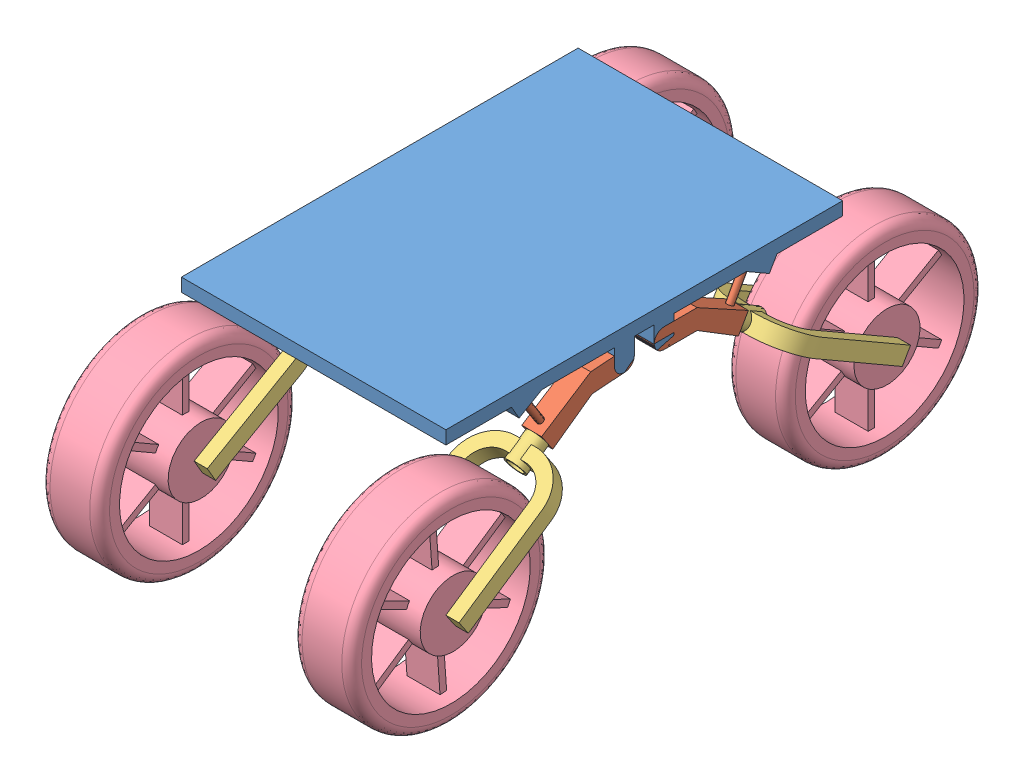
SolidWorks assembly Montagem, configuration Default. Lengths in mm.
Overall size (512.03 470.84 1081.65).
21 component instances, 4 part files, 4 mates.
Components (placement in the parent):
- Base_Boneco-1: Base_Boneco [Default] at (96.9313 339.3056 509.7897) size (400 60 600)
- Amortecimento&Motor-1: Amortecimento&Motor [Default] at (-88.0687 314.3056 479.7897) x (0 0 -1) z (1 0 0) size (523.5 434.65 142.03)
  - Suporte_Rodas-1: Suporte_Rodas [Default] at origin size (166.98 93.59 30)
  - Chave&Motor-1: Chave&Motor [Default] at (303.5974 -146.4145 0) x (0 0 1) z (-0.5 -0.866025 0) size (142.03 362 300)
    - Chave_Motor-1: Chave_Motor [Default] at origin size (142.03 220 30)
    - Motor_Roda-2: Motor_Roda [Default] x (0 0 -1) z (1 0 0) size (300 300 97)
- Amortecimento&Motor-2: Amortecimento&Motor [Default] at (281.9313 314.3056 479.7897) x (0 0 -1) z (1 0 0) size (523.5 434.65 142.03)
  - Suporte_Rodas-1: Suporte_Rodas [Default] at origin size (166.98 93.59 30)
  - Chave&Motor-1: Chave&Motor [Default] at (303.5974 -146.4145 0) x (0 0 1) z (-0.5 -0.866025 0) size (142.03 362 300)
    - Chave_Motor-1: Chave_Motor [Default] at origin size (142.03 220 30)
    - Motor_Roda-2: Motor_Roda [Default] x (0 0 -1) z (1 0 0) size (300 300 97)
- Amortecimento&Motor-3: Amortecimento&Motor [Default] at (-88.0687 314.3056 539.7897) x (0 0 1) z (-1 0 0) size (523.5 434.65 142.03)
  - Suporte_Rodas-1: Suporte_Rodas [Default] at origin size (166.98 93.59 30)
  - Chave&Motor-1: Chave&Motor [Default] at (303.5974 -146.4145 0) x (0 0 1) z (-0.5 -0.866025 0) size (142.03 362 300)
    - Chave_Motor-1: Chave_Motor [Default] at origin size (142.03 220 30)
    - Motor_Roda-2: Motor_Roda [Default] x (0 0 -1) z (1 0 0) size (300 300 97)
- Amortecimento&Motor-4: Amortecimento&Motor [Default] at (281.9313 314.3056 539.7897) x (0 -0.07125 0.997458) z (-1 0 0) size (523.5 434.65 142.03)
  - Suporte_Rodas-1: Suporte_Rodas [Default] at origin size (166.98 93.59 30)
  - Chave&Motor-1: Chave&Motor [Default] at (303.5974 -146.4145 0) x (0 0 1) z (-0.5 -0.866025 0) size (142.03 362 300)
    - Chave_Motor-1: Chave_Motor [Default] at origin size (142.03 220 30)
    - Motor_Roda-2: Motor_Roda [Default] x (0 0 -1) z (1 0 0) size (300 300 97)
Mates (geometry in assembly coordinates):
- Coincident9: coincident: circle of Base_Boneco-1; circle of Amortecimento&Motor-1/Suporte_Rodas-1
- Coincident10: coincident: circle of Base_Boneco-1; circle of Amortecimento&Motor-3/Suporte_Rodas-1
- Coincident11: coincident: circle of Base_Boneco-1; circle of Amortecimento&Motor-4/Suporte_Rodas-1
- Coincident12: coincident: circle of Base_Boneco-1; circle of Amortecimento&Motor-2/Suporte_Rodas-1
